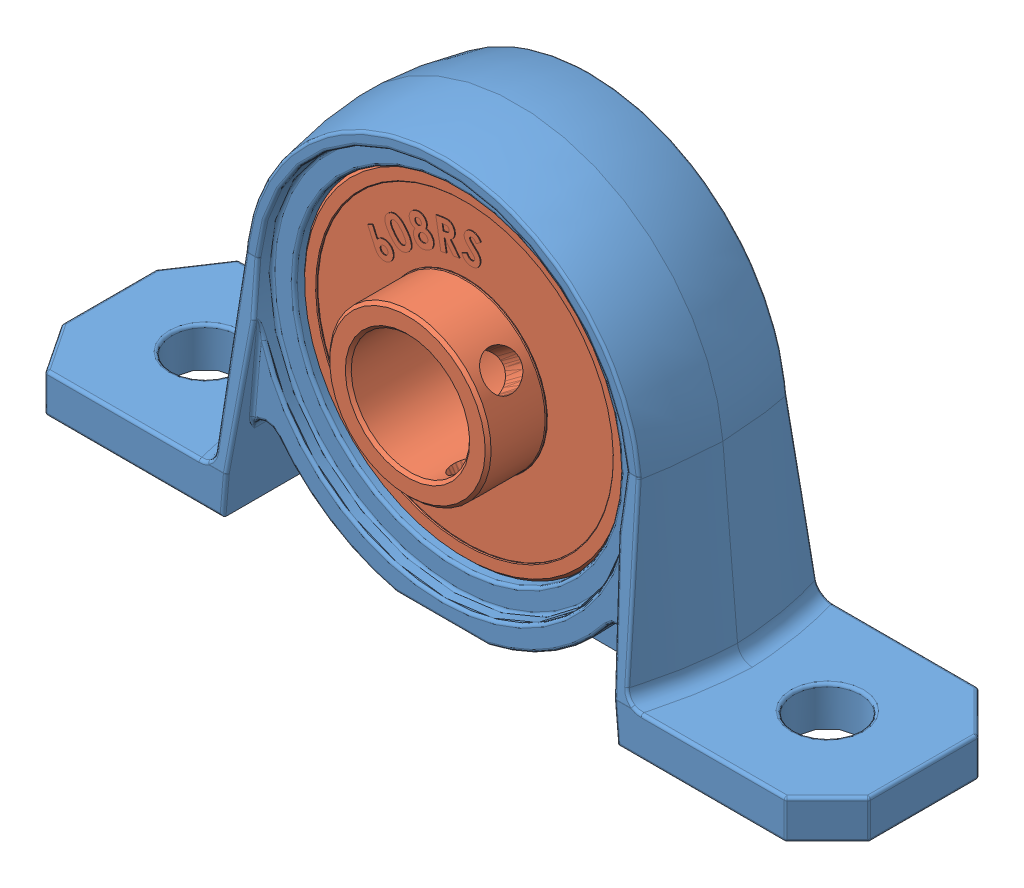
SolidWorks assembly KP08, configuration Default. Lengths in mm.
Overall size (55 38.53 13.92).
2 component instances, 2 part files, 4 mates.
Components (placement in the parent):
- KP08-2: KP08 [По умолчанию] at (2.2899 13.65 0) size (55 38.53 13.13)
- 608RS-1-2: 608RS-1 [Default] at (2.2899 13.65 -3.5) x (0.16403 0.986455 0) z (0 0 1) size (22 22 10.85)
Mates (geometry in assembly coordinates):
- Концентричный2: concentric: cylinder of KP08-2 through (2.2899 16 5) axis (0 0 -1) radius 11; cylinder of 608RS-1-2 through (2.2899 16 3.5) axis (0 0 -1) radius 11
- Расстояние1: distance = 0.5 mm: plane of 608RS-1-2 through (2.2899 13.65 -3.5) normal (0 0 -1); plane of KP08-2 through (2.2899 13.65 -4) normal (0 0 -1)
- Совпадение2: coincident: circle of assembly; circle of KP08-2; plane of assembly
- Совпадение3: coincident: plane of assembly; plane of KP08-2 through (-25.2101 2.35 -6.5) normal (0 -1 0); plane of assembly
